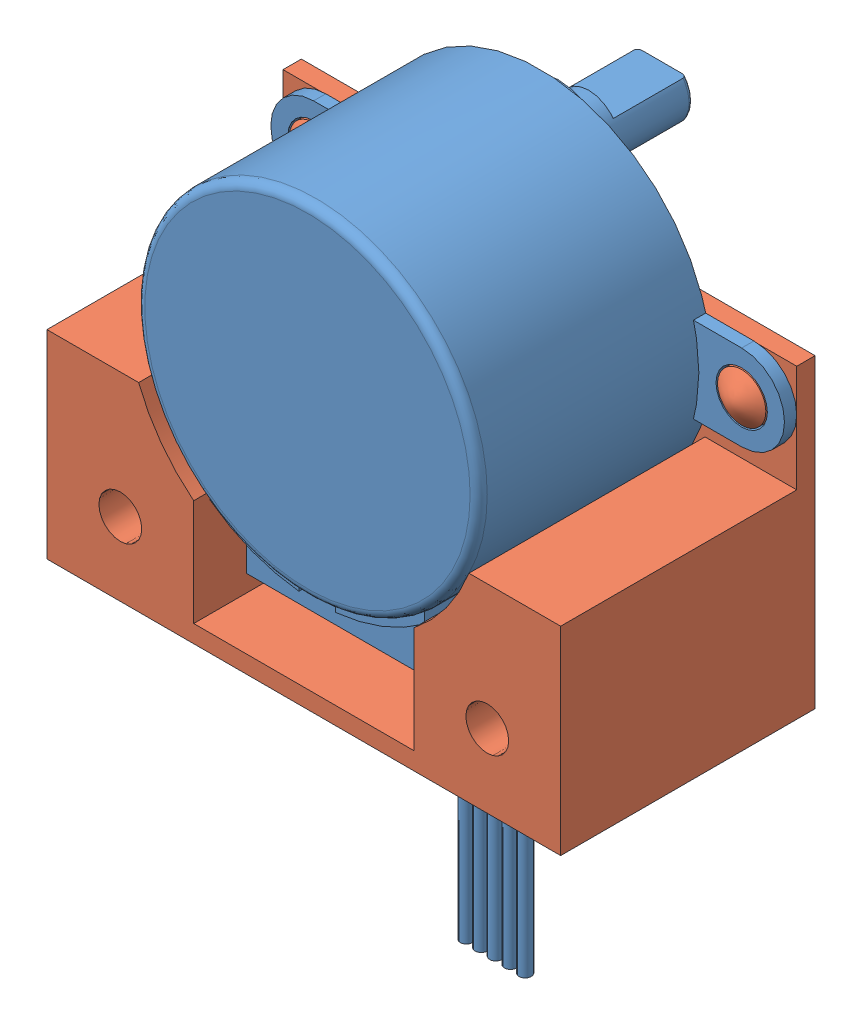
SolidWorks assembly stepper_holder_flat, configuration Default. Lengths in mm.
Overall size (42 61 29.32).
2 component instances, 2 part files, 2 mates.
Components (placement in the parent):
- Step Motor (28BYJ-48)-1: Step Motor (28BYJ-48) [Varsayılan] at (21.2606 45.5238 45.0393) size (42 61 29.02)
- stepper_holder_28BYJ-48-flat-1: stepper_holder_28BYJ-48-flat [Default] at (20.4592 39.4575 43.5393) x (1 0 0) z (0 -1 0) size (42 20.8 25)
Mates (geometry in assembly coordinates):
- Coincident1: coincident anti-aligned: plane of Step Motor (28BYJ-48)-1 through (21.2606 45.5238 45.0393) normal (0 0 -1); plane of stepper_holder_28BYJ-48-flat-1 through (21.4151 43.339 45.0393) normal (0 0 1)
- Concentric1: concentric anti-aligned: circle of Step Motor (28BYJ-48)-1; circle of stepper_holder_28BYJ-48-flat-1
